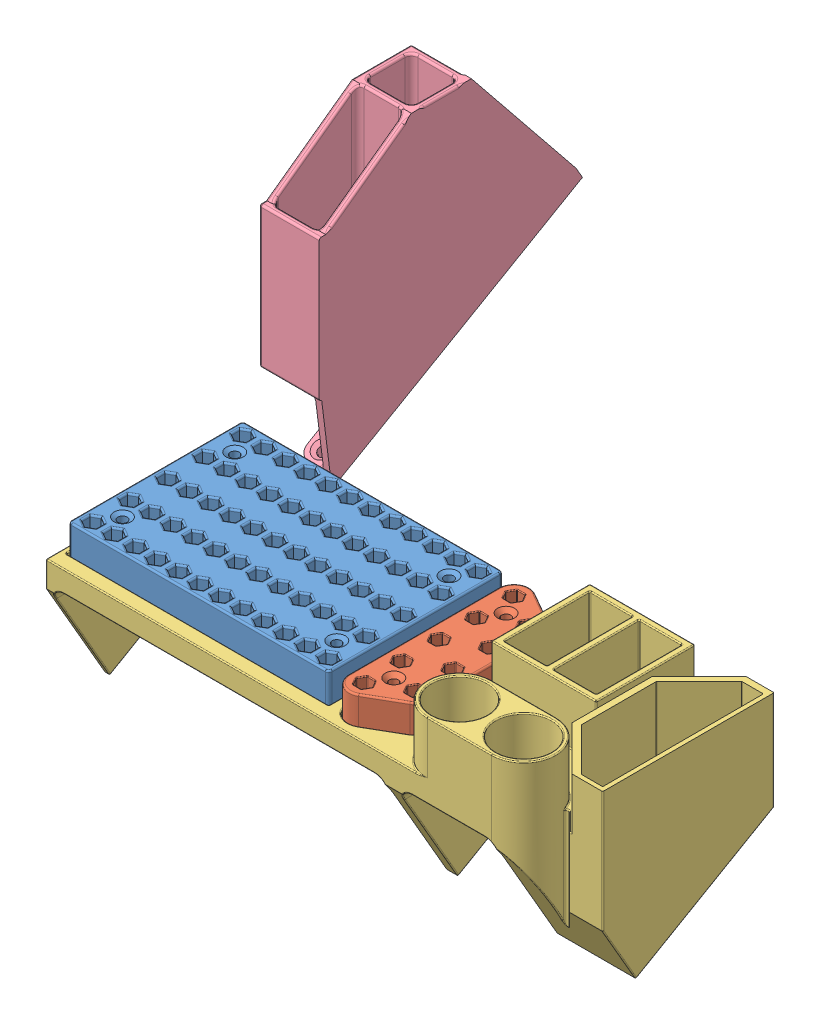
SolidWorks assembly Bit Storage, configuration Default. Lengths in mm.
Overall size (250.5 180.17 225.15).
4 component instances, 4 part files, 12 mates.
Components (placement in the parent):
- just bits hex 2-1: just bits hex 2 [Default] at (0 3.6 0) size (121.59 17.89 81.44)
- socket Hex Holder-1: socket Hex Holder [Default] at (127.9375 1.5875 1.35) x (0 0 -1) z (1 0 0) size (84.14 17.46 29.41)
- Part2^Bit Storage-1: Part2^Bit Storage [Default] at origin size (248 84.52 92.1) (virtual)
- Pliers Mount Messing Around-1: Pliers Mount Messing Around [Default] at (2.7052 95.2982 -145.8539) size (28 132.39 122.85)
Mates (geometry in assembly coordinates):
- Coincident1: coincident anti-aligned: plane of just bits hex 2-1 through (0 0 -34.925) normal (0 -1 0)
- Coincident2: coincident anti-aligned: plane of just bits hex 2-1 through (0 0 -34.925) normal (0 -1 0)
- Coincident3: coincident aligned: plane of just bits hex 2-1 through (0 3.6 0) normal (1 0 0)
- Coincident4: coincident aligned: plane of just bits hex 2-1 through (0 3.6 0) normal (0 0 1)
- Coincident5: coincident anti-aligned: plane of socket Hex Holder-1 through (127.9375 0 1.35) normal (0 -1 0)
- Coincident6: coincident aligned: plane of just bits hex 2-1 through (-5 -146.3407 5.7938) normal (0 0 1); plane of socket Hex Holder-1
- Distance1: distance = 5 mm anti-aligned: plane of just bits hex 2-1 through (115.7938 -146.3407 5) normal (1 0 0); cylinder of socket Hex Holder-1 through (127.9375 0 1.35) axis (0 1 0) radius 7.1437
- Parallel1: parallel anti-aligned: plane of socket Hex Holder-1 through (120.7938 0 -80.8733) normal (-1 0 0)
- Tangent2: tangent aligned: plane of just bits hex 2-1 through (115 -146.3407 -75.6438) normal (0 0 -1); cylinder of socket Hex Holder-1 through (127.9375 0 -68.5) axis (0 1 0) radius 7.1437
- Coincident7: coincident aligned: plane of Part2^Bit Storage-1 through (-8.7938 -12.9904 -86.1438) normal (0 -0.866025 -0.5); plane of Pliers Mount Messing Around-1 through (196.3762 23.687 -149.6709) normal (0 -0.866025 -0.5)
- Coincident8: coincident: plane of Part2^Bit Storage-1 through (-8.7938 -10 11.4937) normal (0 -0.5 0.866025); line of Pliers Mount Messing Around-1 through (213.7052 -54.5211 -14.2105) axis (1 0 0)
- Symmetric1: symmetric aligned: plane of Part2^Bit Storage-1 through (239.2042 -54.5211 1.3562) normal (1 0 0); plane of Pliers Mount Messing Around-1 through (-8.7938 0 0) normal (-1 0 0); plane of Part2^Bit Storage-1 through (115.2052 95.2982 -145.8539) normal (-1 0 0)
